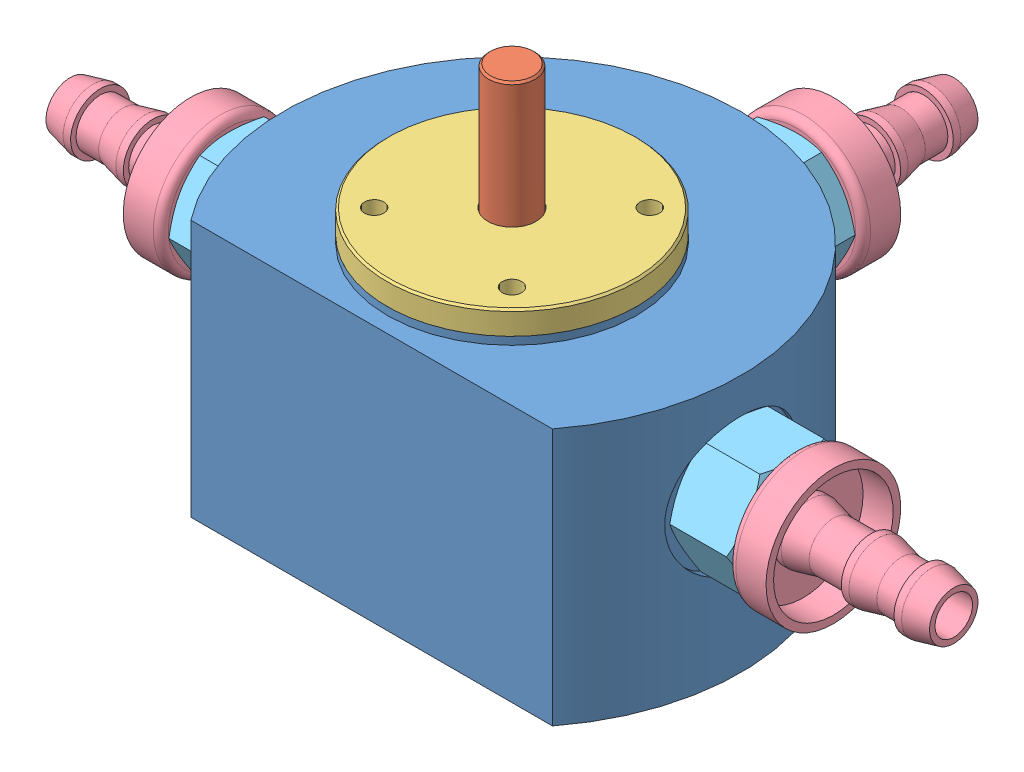
SolidWorks assembly Montagem_Shutter_v10, configuration Default. Lengths in mm.
Overall size (113.34 53 77.18).
15 component instances, 6 part files, 11 mates.
Components (placement in the parent):
- Sede_Inferior_v10-1: Sede_Inferior_v10 [Valor predeterminado<Como usinado>] at origin size (58.71 34 47.36)
- Desviador_v10.5-1: Desviador_v10.5 [Valor predeterminado] x (-0.999999 0 -0.001148) z (0.001148 0 -0.999999) size (18 50.5 18)
- Sede_superior_v10-1: Sede_superior_v10 [Valor predeterminado] at (0 15.5 0) x (0.939693 0 -0.34202) z (0.34202 0 0.939693) size (32 4 32)
- B_PB4_PM4_25940-2: B_PB4_PM4_25940 [Valor predeterminado] at (-56.6723 0 0) x (1 0 0) z (0 -0.022845 0.999739) size (42.67 17.27 17.27)
  - PRODUCT_NAME_1-1: PRODUCT_NAME_1 [Valor predeterminado] at origin size (20.27 17.27 17.27)
  - PRODUCT_NAME_2-1: PRODUCT_NAME_2 [Valor predeterminado] at origin size (22.4 14.29 16.5)
- B_PB4_PM4_25940-5: B_PB4_PM4_25940 [Valor predeterminado] at (0 0 -56.6723) x (0 0 1) z (-0.999739 -0.022845 0) size (42.67 17.27 17.27)
  - PRODUCT_NAME_1-1: PRODUCT_NAME_1 [Valor predeterminado] at origin size (20.27 17.27 17.27)
  - PRODUCT_NAME_2-1: PRODUCT_NAME_2 [Valor predeterminado] at origin size (22.4 14.29 16.5)
- B_PB4_PM4_25940-6: B_PB4_PM4_25940 [Valor predeterminado] at (56.6723 0 0) x (-1 0 0) z (0 -0.022845 -0.999739) size (42.67 17.27 17.27)
  - PRODUCT_NAME_1-1: PRODUCT_NAME_1 [Valor predeterminado] at origin size (20.27 17.27 17.27)
  - PRODUCT_NAME_2-1: PRODUCT_NAME_2 [Valor predeterminado] at origin size (22.4 14.29 16.5)
- Sede_Vedacao-4: Sede_Vedacao [Valor predeterminado] at (-8.0003 0 0) x (-1 0 0) z (0 0 -1) size (6.38 12.7 12.7)
- Sede_Vedacao-5: Sede_Vedacao [Valor predeterminado] at (0 0 -8.0003) x (0 0 -1) z (1 0 0) size (6.38 12.7 12.7)
- Sede_Vedacao-6: Sede_Vedacao [Valor predeterminado] at (8.0003 0 0) size (6.38 12.7 12.7)
Mates (geometry in assembly coordinates):
- Coincident1: coordinate: point of Sede_Inferior_v10-1; point of assembly
- Concentric1: concentric aligned: cylinder of Sede_Inferior_v10-1 through (0 -20 0) axis (0 -1 0) radius 3; cylinder of Desviador_v10.5-1 through (0 0 0) axis (0 -1 0) radius 3
- Coincident2: coincident anti-aligned: plane of Sede_Inferior_v10-1 through (9 -13 0) normal (0 1 0); plane of Desviador_v10.5-1 through (-3 -13 -0.0034) normal (0 -1 0)
- Concêntrico1: concentric aligned: cylinder of Desviador_v10.5-1 through (0 0 0) axis (0 -1 0) radius 3; cylinder of Sede_superior_v10-1 through (0 15.5 0) axis (0 -1 0) radius 3.1
- Coincidente3: coincident anti-aligned: plane of Sede_superior_v10-1 through (8.4572 14 -3.0782) normal (0 -1 0); plane of Sede_Inferior_v10-1 through (0 14 0) normal (0 1 0)
- Concêntrico4: concentric aligned: cylinder of Sede_Inferior_v10-1 through (8.8388 14 8.8388) axis (0 1 0) radius 1.25; cylinder of Sede_superior_v10-1 through (8.8388 17 8.8388) axis (0 1 0) radius 1.25
- Concêntrico5: concentric anti-aligned: cylinder of Sede_Inferior_v10-1 through (-29.356 0 0) axis (-1 0 0) radius 5.9436; cone of B_PB4_PM4_25940-2/PRODUCT_NAME_2-1 through (-23.4752 0 0) axis (1 0 0)
- Coincidente4: coincident anti-aligned: plane of Sede_Inferior_v10-1 through (-27.856 0 0) normal (-1 0 0); plane of B_PB4_PM4_25940-2/PRODUCT_NAME_2-1 through (-27.856 -6.4387 -0.1471) normal (1 0 0)
- Concêntrico8: concentric anti-aligned: cylinder of Sede_Inferior_v10-1 through (-29.356 0 0) axis (-1 0 0) radius 5.9436; cylinder of Sede_Vedacao-4 through (-22.2667 0 0) axis (1 0 0) radius 6.35
- Coincidente6: coincident anti-aligned: plane of Sede_Vedacao-4 through (-8.0003 0 0) normal (0 0 -1); plane of assembly through (0 0 0) normal (0 0 1)
- Coincidente8: coincident anti-aligned: plane of B_PB4_PM4_25940-2/PRODUCT_NAME_2-1 through (-14.0003 -4.491 -0.1026) normal (1 0 0); plane of Sede_Vedacao-4 through (-14.0003 5.5 0) normal (-1 0 0)
